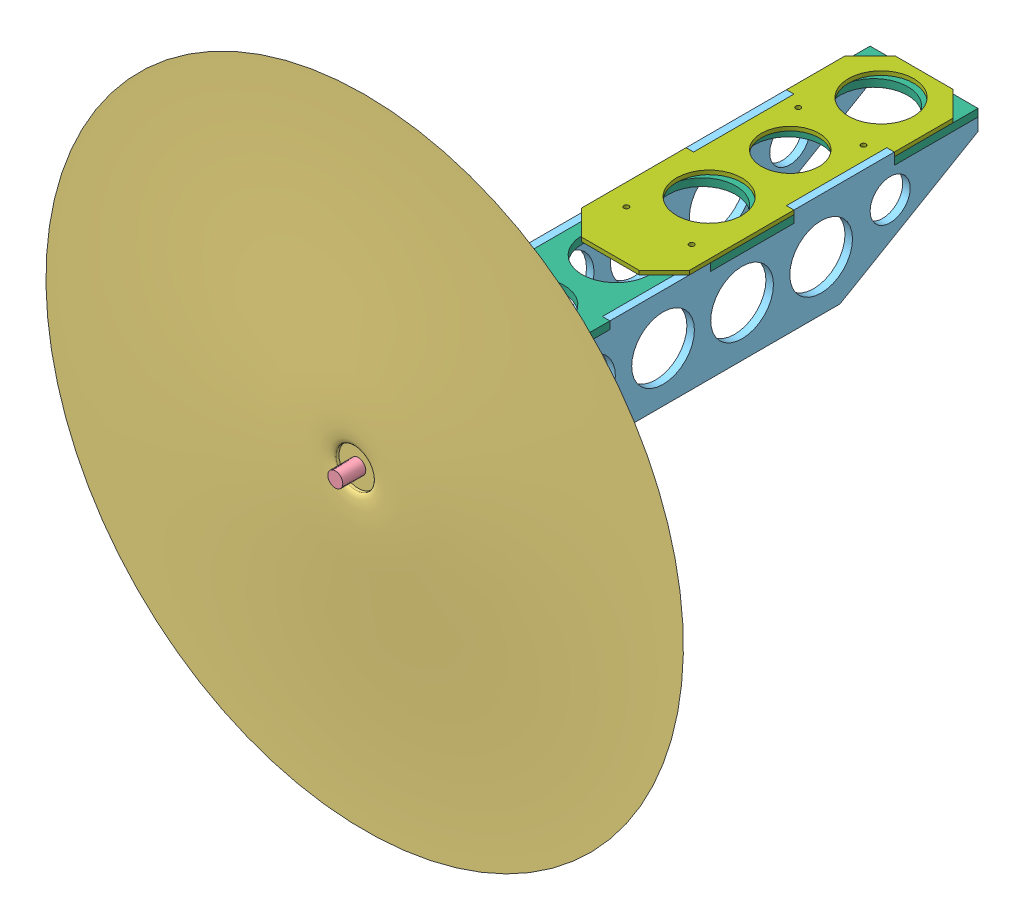
SolidWorks assembly propulsion_assembly, configuration Default. Lengths in mm.
Overall size (354.83 354.83 234.6).
8 component instances, 7 part files, 17 mates.
Components (placement in the parent):
- wing_motor_mount-1: wing_motor_mount [Default] at (11.8708 21.991 23.464) size (43 40 3)
- motormount-1: motormount [Default] at (11.8708 21.991 26.464) x (0.707107 0.707107 0) z (0 0 1) size (46 46 3)
- prop-1: prop [Default] at (11.8708 21.991 69.3605) x (-0.808587 0.588377 0) z (0.588377 0.808587 0) size (254 13.3 254)
- 2218motor-1: 2218motor [Default] at (11.8708 21.991 29.464) x (0.322129 -0.946696 0) z (0 0 1) size (27.7 27.7 51.6)
- wing_motor_mount_side-1: wing_motor_mount_side [Default] at (-9.6292 43.491 26.464) size (3 41.6 184)
- wing_motor_mount_side-2: wing_motor_mount_side [Default] at (30.3708 43.491 26.464) size (3 41.6 184)
- wing_motormount_top-1: wing_motormount_top [Default] at (11.8708 40.491 26.464) x (0 0 -1) z (1 0 0) size (184 3 43)
- wing_flange-1: wing_flange [Default] at (11.8708 43.491 -28.536) x (0 0 -1) z (1 0 0) size (125 1.6 43)
Mates (geometry in assembly coordinates):
- Coincident1: coincident anti-aligned: plane of wing_motor_mount-1 through (11.8708 21.991 26.464) normal (0 0 1); plane of motormount-1 through (11.8708 21.991 26.464) normal (0 0 -1)
- Concentric1: concentric anti-aligned: circle of wing_motor_mount-1; cylinder of motormount-1 through (-0.5036 34.3654 29.464) axis (0 0 -1) radius 1.5
- Concentric2: concentric aligned: circle of wing_motor_mount-1; circle of motormount-1
- Concentric3: concentric aligned: cylinder of motormount-1 through (11.8708 21.991 29.464) axis (0 0 -1) radius 15; cylinder of 2218motor-1 through (11.8708 21.991 63.064) axis (0 0 -1) radius 13.85
- Coincident4: coincident anti-aligned: plane of motormount-1 through (11.8708 21.991 29.464) normal (0 0 1); plane of 2218motor-1 through (11.8708 21.991 29.464) normal (0 0 -1)
- Concentric4: concentric aligned: circle of prop-1; cylinder of 2218motor-1 through (11.8708 21.991 63.064) axis (0 0 -1) radius 13.85
- Tangent1: tangent: plane of assembly; face of prop-1; plane of 2218motor-1 through (11.8708 21.991 63.064) normal (0 0 1)
- Coincident5: coincident anti-aligned: plane of wing_motor_mount-1 through (-6.6292 31.491 23.464) normal (-1 0 0); plane of wing_motor_mount_side-1 through (-6.6292 43.491 26.464) normal (1 0 0)
- Coincident6: coincident anti-aligned: plane of wing_motor_mount-1 through (30.3708 31.491 23.464) normal (1 0 0); plane of wing_motor_mount_side-2 through (30.3708 43.491 26.464) normal (-1 0 0)
- Coincident9: coincident aligned: plane of wing_motor_mount-1 through (-6.6292 40.491 23.464) normal (0 1 0); plane of wing_motor_mount_side-1 through (-6.6292 40.491 26.464) normal (0 1 0)
- Coincident10: coincident aligned: plane of wing_motor_mount-1 through (30.3708 40.491 23.464) normal (0 1 0); plane of wing_motor_mount_side-2 through (33.3708 40.491 26.464) normal (0 1 0)
- Coincident11: coincident aligned: plane of wing_motor_mount-1 through (-9.6292 43.491 26.464) normal (0 1 0); plane of wing_motormount_top-1 through (11.8708 43.491 26.464) normal (0 1 0)
- Coincident12: coincident aligned: plane of wing_motor_mount_side-2 through (33.3708 43.491 26.464) normal (1 0 0); plane of wing_motormount_top-1 through (33.3708 43.491 26.464) normal (1 0 0)
- Coincident13: coincident anti-aligned: plane of wing_motor_mount_side-2 through (33.3708 43.491 -120.2027) normal (0 0 -1); plane of wing_motormount_top-1 through (11.8708 43.491 -120.2027) normal (0 0 1)
- Coincident14: coincident anti-aligned: plane of wing_motor_mount_side-2 through (30.3708 43.491 26.464) normal (-1 0 0); plane of wing_flange-1 through (30.3708 45.091 -28.536) normal (1 0 0)
- Coincident15: coincident anti-aligned: plane of wing_motor_mount_side-2 through (33.3708 43.491 -120.2027) normal (0 0 -1); plane of wing_flange-1 through (11.8708 45.091 -120.2027) normal (0 0 1)
- Coincident16: coincident aligned: plane of wing_motor_mount_side-2 through (30.3708 45.091 -80.2027) normal (0 1 0); plane of wing_flange-1 through (11.8708 45.091 -28.536) normal (0 1 0)
